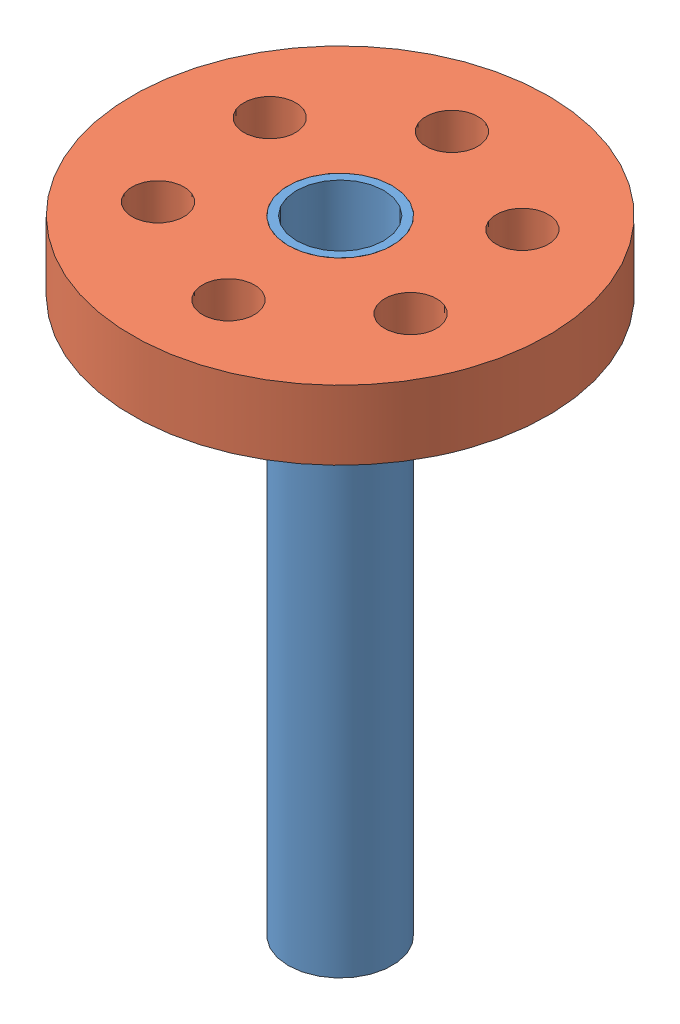
SolidWorks assembly disk and peg fixture, configuration Default. Lengths in mm.
Overall size (33.18 38.1 33.18).
2 component instances, 2 part files, 1 mates.
Components (placement in the parent):
- peg-1: peg [Default] at origin size (6.35 38.1 6.35)
- disk-1: disk [Default] at (0 16.9333 0) x (0.382153 0 -0.924099) z (0.924099 0 0.382153) size (25.4 4.23 25.4)
Mates (geometry in assembly coordinates):
- Hinge1: hinge aligned: circle of disk-1; cylinder of peg-1 through (0 19.05 0) axis (0 -1 0) radius 3.175; plane of disk-1 through (0 19.05 0) normal (0 1 0); plane of peg-1 through (0 19.05 0) normal (0 1 0)
